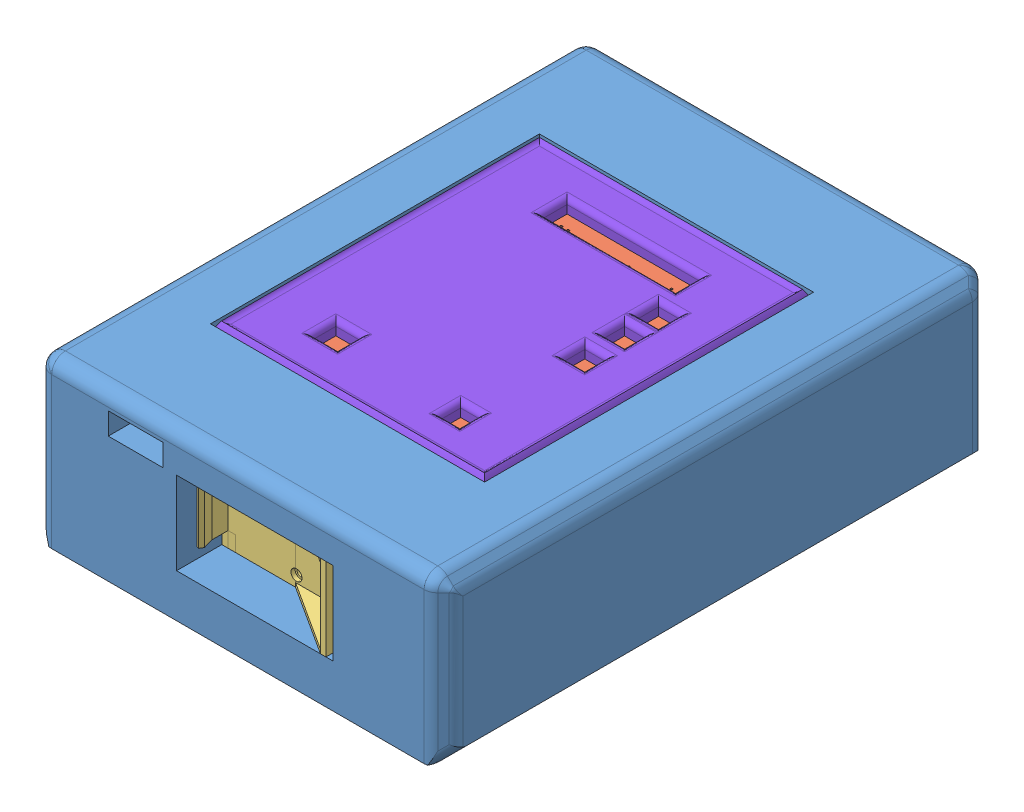
SolidWorks assembly ProjectAssembly, configuration Default. Lengths in mm.
Overall size (150 60.9 200).
14 component instances, 10 part files, 9 mates.
Components (placement in the parent):
- labProject_micro_bottom-1: labProject_micro_bottom [Default] at (62.4415 65.408 166.0498) x (0 0 -1) z (1 0 0) size (200 60 150)
- AlarmTiming.step-2: AlarmTiming.step [Default] at (129.4415 115.5655 258.5498) x (0 0 -1) z (0 1 0) size (103.51 82.17 0.41)
  - Board.step-1: Board.step [Default] at origin size (103.51 82.17 0.41)
    - Open CASCADE STEP translator 6.8 6.1.1.step-1: Open CASCADE STEP translator 6.8 6.1.1.step [Default] at (0 0 -0.4115) size (103.51 82.17 0.41)
- BatteryHolder_9V_Eyelet_or_Pins-1: BatteryHolder_9V_Eyelet_or_Pins [Default] at (67.3181 96.3201 247.0498) size (62.36 30.2 20.5)
  - BatteryHolder_9V_Eyelet_or_Pins.step-1: BatteryHolder_9V_Eyelet_or_Pins.step [Default] at origin size (62.36 30.2 29.4)
    - Body_Housing.step-1: Body_Housing.step [Default] at origin size (54.5 30.2 20.5)
    - Body_Anode.step-1: Body_Anode.step [Default] at (22 -6.35 11.5) size (4.62 9.24 8)
    - Body_Cathode.step-1: Body_Cathode.step [Default] at (22 6.35 11.5) size (4.62 7.3 7.3)
    - Body_Pin.step-1: Body_Pin.step [Default] at origin size (0.8 0.8 19.4) (hidden)
    - Array_Pins.step-1: Array_Pins.step [Default] at origin size (0.8 13.5 19.4) (hidden)
    - Eyelet_bended_Cathode.step-1: Eyelet_bended_Cathode.step [Default] at (26.6 6.35 11.5) x (0 1 0) z (1 0 0) size (5.54 13.94 8.51)
    - Eyelet_bended_Anode.step-1: Eyelet_bended_Anode.step [Default] at (26.6 -6.35 11.5) x (0 1 0) z (1 0 0) size (5.54 13.94 8.51)
- labProject_micro_top-1: labProject_micro_top [Default] at (62.4415 130.3115 166.0498) x (0 0 -1) z (-1 0 0) size (120 10.75 100)
Mates (geometry in assembly coordinates):
- Concentric3: concentric anti-aligned: cone of labProject_micro_bottom-1 through (25.4415 116.654 213.5498) axis (0 1 0); cylinder of AlarmTiming.step-2/Board.step-1/Open CASCADE STEP translator 6.8 6.1.1.step-1 through (25.4415 115.154 213.5498) axis (0 -1 0) radius 2
- Concentric4: concentric anti-aligned: cone of labProject_micro_bottom-1 through (25.4415 116.654 118.5498) axis (0 1 0); cylinder of AlarmTiming.step-2/Board.step-1/Open CASCADE STEP translator 6.8 6.1.1.step-1 through (25.4415 115.154 118.5498) axis (0 -1 0) radius 2
- Coincident1: coincident anti-aligned: plane of labProject_micro_bottom-1 through (25.4415 115.154 118.5498) normal (0 1 0); plane of AlarmTiming.step-2/Board.step-1/Open CASCADE STEP translator 6.8 6.1.1.step-1 through (103.9145 115.154 217.5288) normal (0 -1 0)
- Coincident5: coincident anti-aligned: plane of labProject_micro_bottom-1 through (40.0681 111.4201 245.5498) normal (0 -1 0); plane of BatteryHolder_9V_Eyelet_or_Pins-1/BatteryHolder_9V_Eyelet_or_Pins.step-1/Body_Housing.step-1 through (66.9681 111.4201 249.5498) normal (0 1 0)
- Coincident6: coincident anti-aligned: plane of labProject_micro_bottom-1 through (62.4415 65.408 245.5498) normal (0 0 1); plane of BatteryHolder_9V_Eyelet_or_Pins-1/BatteryHolder_9V_Eyelet_or_Pins.step-1/Body_Housing.step-1 through (41.8757 108.6125 245.5498) normal (0 0 -1)
- Coincident7: coincident anti-aligned: plane of labProject_micro_bottom-1 through (40.0681 111.4201 245.5498) normal (1 0 0); plane of BatteryHolder_9V_Eyelet_or_Pins-1/BatteryHolder_9V_Eyelet_or_Pins.step-1/Body_Housing.step-1 through (40.0681 81.2201 247.0498) normal (-1 0 0)
- Concentric6: concentric: cone of labProject_micro_bottom-1 through (99.4415 116.654 213.5498) axis (0 1 0); cone of labProject_micro_top-1 through (99.4415 228.7254 213.5498) axis (0 1 0)
- Concentric7: concentric: cylinder of labProject_micro_bottom-1 through (99.4415 116.654 118.5498) axis (0 -1 0) radius 1.6; cone of labProject_micro_top-1 through (99.4415 228.7254 118.5498) axis (0 1 0)
- Coincident9: coincident anti-aligned: plane of AlarmTiming.step-2/Board.step-1/Open CASCADE STEP translator 6.8 6.1.1.step-1 through (103.9145 115.5655 217.5288) normal (0 1 0); plane of labProject_micro_top-1 through (99.4415 115.5655 213.5498) normal (0 -1 0)
